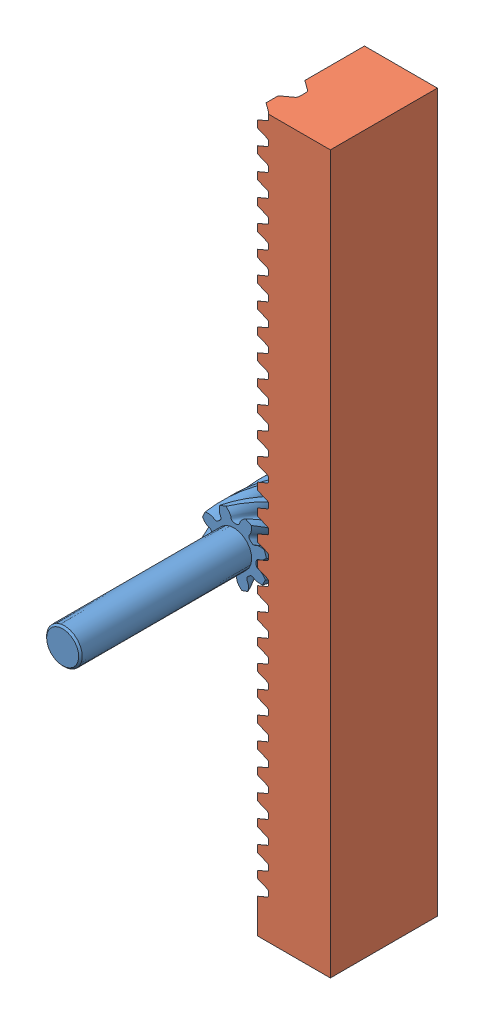
SolidWorks assembly RACK AND PINION, configuration Default. Lengths in mm.
Overall size (40.37 204.2 78).
2 component instances, 2 part files, 6 mates.
Components (placement in the parent):
- PINION-1: PINION [GearTrax] x (-0.665872 0.746066 0) z (0 0 1) size (18.86 18.86 78)
- RACK-1: RACK [GearTrax] at (8 107.1457 0) size (20.44 204.2 30)
Mates (geometry in assembly coordinates):
- Coincident1: coincident aligned: plane of PINION-1 through (0 0 0) normal (0 0 1); plane of assembly through (0 0 0) normal (0 0 1)
- Coincident2: coincident aligned: line of PINION-1 through (0 0 55) axis (0 0 -1); plane of assembly
- Coincident3: coincident aligned: line of PINION-1 through (0 0 55) axis (0 0 -1); plane of assembly
- Coincident4: coincident aligned: plane of PINION-1 through (0 0 0) normal (0 0 1); plane of RACK-1 through (8 107.1457 0) normal (0 0 1)
- Distance1: distance = 8 mm aligned: plane of RACK-1 through (8 107.1457 0) normal (1 0 0); plane of assembly through (0 0 0) normal (1 0 0)
- RackPinionMate1: rack pinion = 16 mm: line of RACK-1 through (110 8 52.1457) axis (0 0 1); circle of PINION-1
